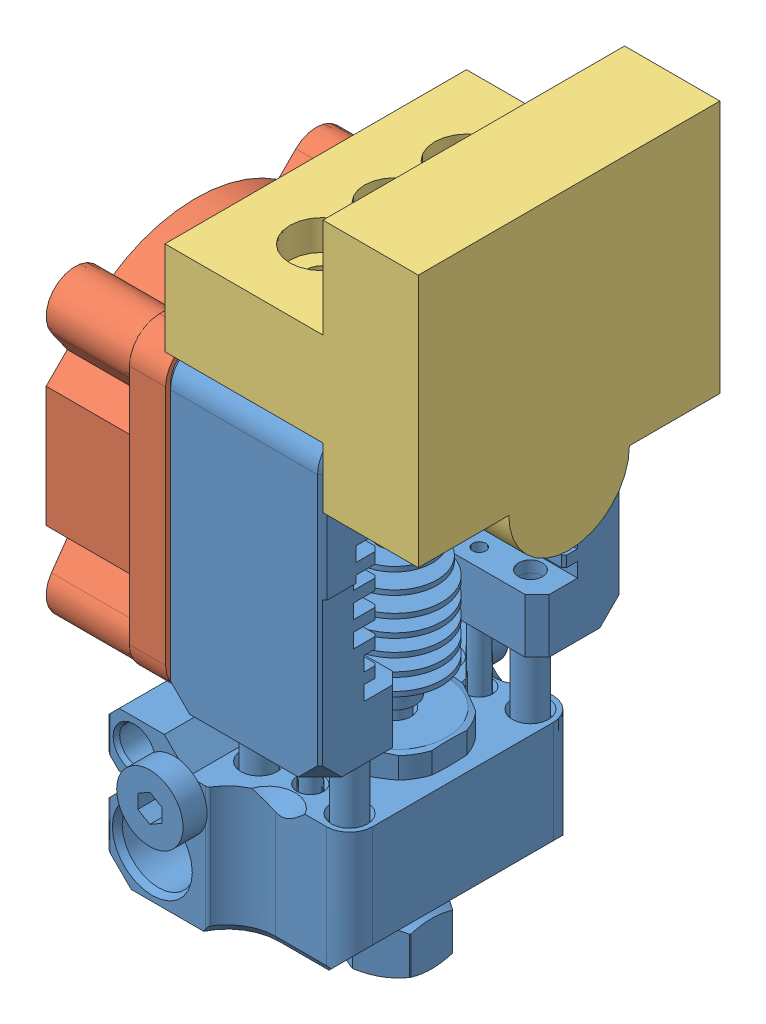
SolidWorks assembly SingleHotendwFan, configuration Default. Lengths in mm.
Overall size (30.95 63 27).
3 component instances, 3 part files, 6 mates.
Components (placement in the parent):
- mosquito_model_to_publish-1: mosquito_model_to_publish [Default] at (12.5766 22.6105 40.0015) size (18.85 47 27)
- fan 20mm-1: fan 20mm [Default] at (6.0766 38.6105 40.0015) x (0 1 0) z (-1 0 0) size (25 25 10.01)
- mosquito_single_mount-1: mosquito_single_mount [Default] at (27.0266 56.6105 40.0016) x (0 0 -1) z (-1 0 0) size (25 26 21)
Mates (geometry in assembly coordinates):
- Coincident1: coincident aligned: plane of mosquito_model_to_publish-1 through (6.0766 48.6105 30.0015) normal (1 0 0); plane of fan 20mm-1 through (6.0766 38.6105 40.0015) normal (1 0 0)
- Concentric1: concentric aligned: cylinder of mosquito_model_to_publish-1 through (6.0766 48.6105 30.0015) axis (-1 0 0) radius 1.4; cylinder of fan 20mm-1 through (6.0766 48.6105 30.0015) axis (-1 0 0) radius 1.4
- Concentric2: concentric aligned: cylinder of mosquito_model_to_publish-1 through (6.0766 48.6105 50.0015) axis (-1 0 0) radius 1.4; cylinder of fan 20mm-1 through (6.0766 48.6105 50.0015) axis (-1 0 0) radius 1.4
- Coincident2: coincident: plane of mosquito_model_to_publish-1 through (19.0766 51.1105 40.0015) normal (0 -1 0); plane of mosquito_single_mount-1 through (27.0266 51.1105 40.0016) normal (0 -1 0)
- Concentric3: concentric: cylinder of mosquito_model_to_publish-1 through (12.5766 51.1105 46.0015) axis (0 1 0) radius 1.025; cylinder of mosquito_single_mount-1 through (12.5766 35.3625 46.0018) axis (0 1 0) radius 1.3498
- Concentric4: concentric anti-aligned: cylinder of mosquito_model_to_publish-1 through (12.5766 51.1105 34.0015) axis (0 1 0) radius 1.025; circle of mosquito_single_mount-1
